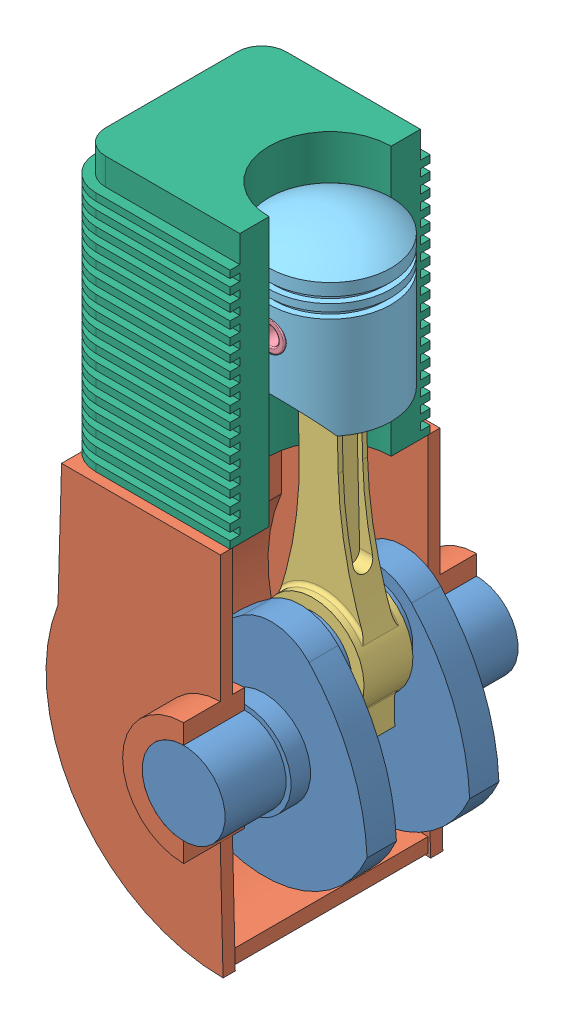
SolidWorks assembly Engine, configuration Default. Lengths in mm.
Overall size (3058.33 6591.3 3048).
6 component instances, 6 part files, 11 mates.
Components (placement in the parent):
- Engine Crank shaft-1: Engine Crank shaft [Default] at (5212.9153 3797.7074 2407.9179) x (0.993211 -0.116325 0) z (0 0 1) size (2235.2 2336.8 3048)
- Engine Lower case-1: Engine Lower case [Default] at (5212.9153 3797.7074 2534.9179) size (1841.5 3797.3 3048)
- Engine Connecting rod-2: Engine Connecting rod [Default] at (5286.7817 4428.3965 1518.9179) x (0.999706 0.024234 0) z (0 0 1) size (1066.8 4067.92 508)
- Engine Gudgen pin-2: Engine Gudgen pin [Default] at (5212.9153 7475.5013 2153.9179) x (0 0 -1) z (1 0 0) size (1270 317.5 317.5)
- Engine Piston-2: Engine Piston [Default] at (5212.9153 6700.8013 1518.9179) x (-1 0 0) z (0 0 -1) size (1270 1587.81 1270)
- Engine uppercase-2: Engine uppercase [Default] at (5212.9153 5753.5074 1518.9179) x (0 0 -1) z (1 0 0) size (2082.8 2794 1752.6)
Mates (geometry in assembly coordinates):
- Coincident1: coincident anti-aligned: circle of Engine Crank shaft-1; circle of Engine Lower case-1
- Concentric17: concentric anti-aligned: cylinder of Engine Gudgen pin-2 through (5212.9153 7475.5013 883.9179) axis (0 0 1) radius 158.75; cylinder of Engine Piston-2 through (5212.9153 7475.5013 2475.2279) axis (0 0 -1) radius 158.75
- Width2: width aligned: plane of Engine Piston-2 through (5212.9153 7475.5013 1823.7179) normal (0 0 -1); plane of Engine Gudgen pin-2 through (5212.9153 7475.5013 1214.1179) normal (0 0 1); plane of Engine Piston-2 through (5212.9153 7475.5013 883.9179) normal (0 0 -1); plane of Engine Gudgen pin-2 through (5212.9153 7475.5013 2153.9179) normal (0 0 1)
- Concentric18: concentric anti-aligned: cylinder of Engine Connecting rod-2 through (5212.9153 7475.5013 1772.9179) axis (0 0 -1) radius 158.75; cylinder of Engine Gudgen pin-2 through (5212.9153 7475.5013 883.9179) axis (0 0 1) radius 158.75
- Width3: width anti-aligned: plane of Engine Piston-2 through (5212.9153 7475.5013 1214.1179) normal (0 0 1); plane of Engine Connecting rod-2 through (5212.9153 7475.5013 1823.7179) normal (0 0 -1); plane of Engine Piston-2 through (5212.9153 7475.5013 1264.9179) normal (0 0 -1); plane of Engine Connecting rod-2 through (5212.9153 7475.5013 1772.9179) normal (0 0 1)
- Concentric19: concentric anti-aligned: cylinder of Engine Crank shaft-1 through (5286.7817 4428.3965 1518.9179) axis (0 0 1) radius 406.4; cylinder of Engine Connecting rod-2 through (5286.7817 4428.3965 1772.9179) axis (0 0 -1) radius 406.4
- Coincident10: coincident anti-aligned: plane of Engine Lower case-1 through (5212.9153 5753.5074 2661.9179) normal (0 1 0); plane of Engine uppercase-2 through (3815.9153 5753.5074 833.1179) normal (0 -1 0)
- Coincident13: coincident: line of Engine Lower case-1 through (5212.9153 5753.5074 375.9179) axis (0 0 1); plane of Engine uppercase-2 through (5212.9153 8547.5074 883.9179) normal (1 0 0)
- Width4: width anti-aligned: plane of Engine Lower case-1 through (5212.9153 3797.7074 375.9179) normal (0 0 -1); plane of Engine uppercase-2 through (5212.9153 3797.7074 2661.9179) normal (0 0 1); plane of Engine Lower case-1 through (5212.9153 8547.5074 2458.7179) normal (0 0 1); plane of Engine uppercase-2 through (5212.9153 8547.5074 579.1179) normal (0 0 -1)
- Width5: width anti-aligned: plane of Engine Crank shaft-1 through (4605.9812 3518.6307 1137.9179) normal (0 0 1); plane of Engine Connecting rod-2 through (4605.9812 3518.6307 1899.9179) normal (0 0 -1); plane of Engine Crank shaft-1 through (5286.7817 4428.3965 1264.9179) normal (0 0 -1); plane of Engine Connecting rod-2 through (5286.7817 4428.3965 1772.9179) normal (0 0 1)
- Concentric23: concentric anti-aligned: cylinder of Engine Piston-2 through (5212.9153 8288.3013 1518.9179) axis (0 1 0) radius 635; cylinder of Engine uppercase-2 through (5212.9153 8547.5074 1518.9179) axis (0 -1 0) radius 635
